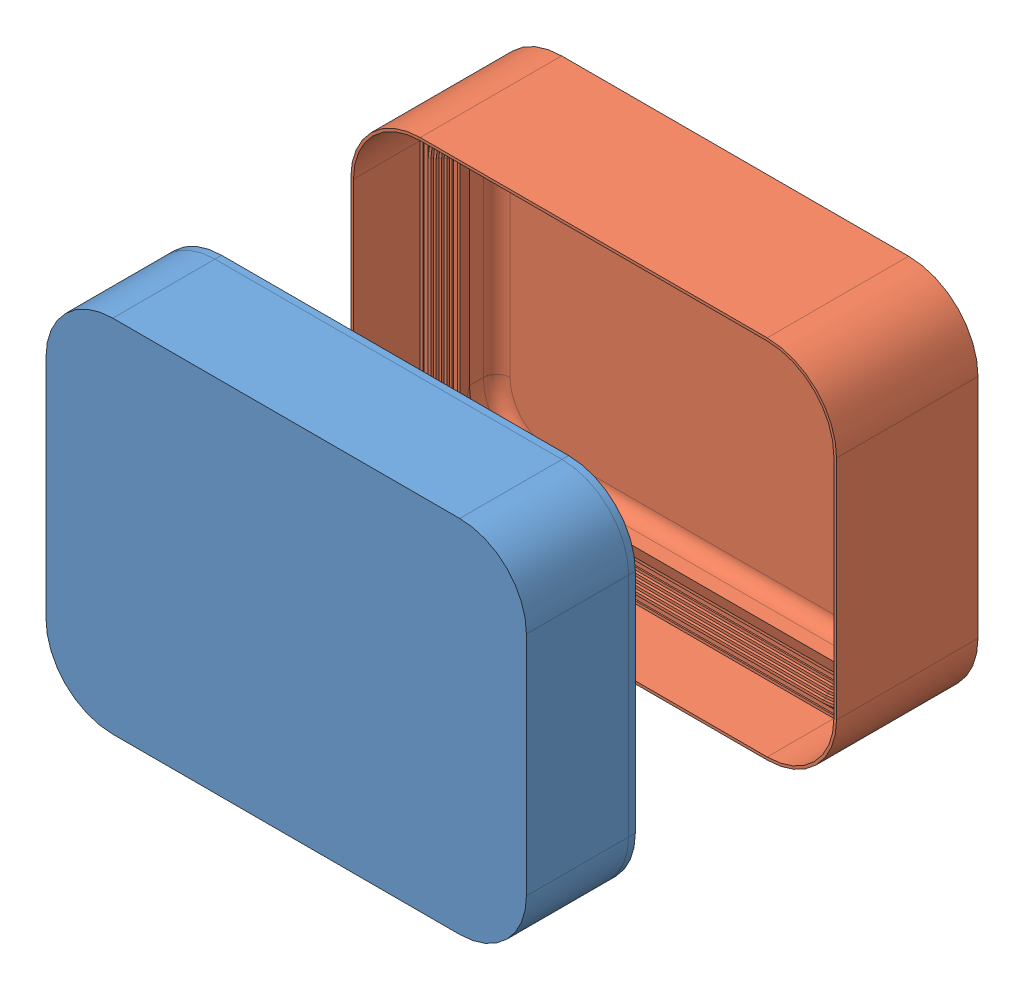
SolidWorks assembly Assemblage1, configuration Défaut. Lengths in mm.
Overall size (72.8 54.8 67.28).
3 component instances, 3 part files, 6 mates.
Components (placement in the parent):
- boitier_balaye-1: boitier_balaye [Défaut] at origin size (72 54 16.32)
- capot-1: capot [Défaut] at (0 0 -64.8806) x (1 0 0) z (0 0 -1) size (72.8 54.8 21.2)
- carte_elec-1: carte_elec [Défaut] at (3.8161 0.8186 -5) x (-1 0 0) z (0 0 -1) size (62 43.2 2)
Mates (geometry in assembly coordinates):
- Parallèle1: parallel aligned: plane of boitier_balaye-1 through (-26 -17 0) normal (0 0 -1); plane of capot-1 through (-26 17 -66.0806) normal (0 0 -1)
- Parallèle2: parallel aligned: plane of boitier_balaye-1 through (0 -27 -14.1228) normal (0 -1 0); plane of carte_elec-1 through (30.9661 -20.7814 -7) normal (0 -1 0)
- Coïncidente5: coincident anti-aligned: plane of boitier_balaye-1 through (26.6661 17.8186 -5) normal (0 0 -1); plane of carte_elec-1 through (3.8161 0.8186 -5) normal (0 0 1)
- Perpendiculaire1: perpendicular: line of capot-1 through (-36 -17 -64.8806) axis (0 1 0)
- Coïncidente11: coincident: point of capot-1
- Coïncidente12: coincident: unknown of capot-1
